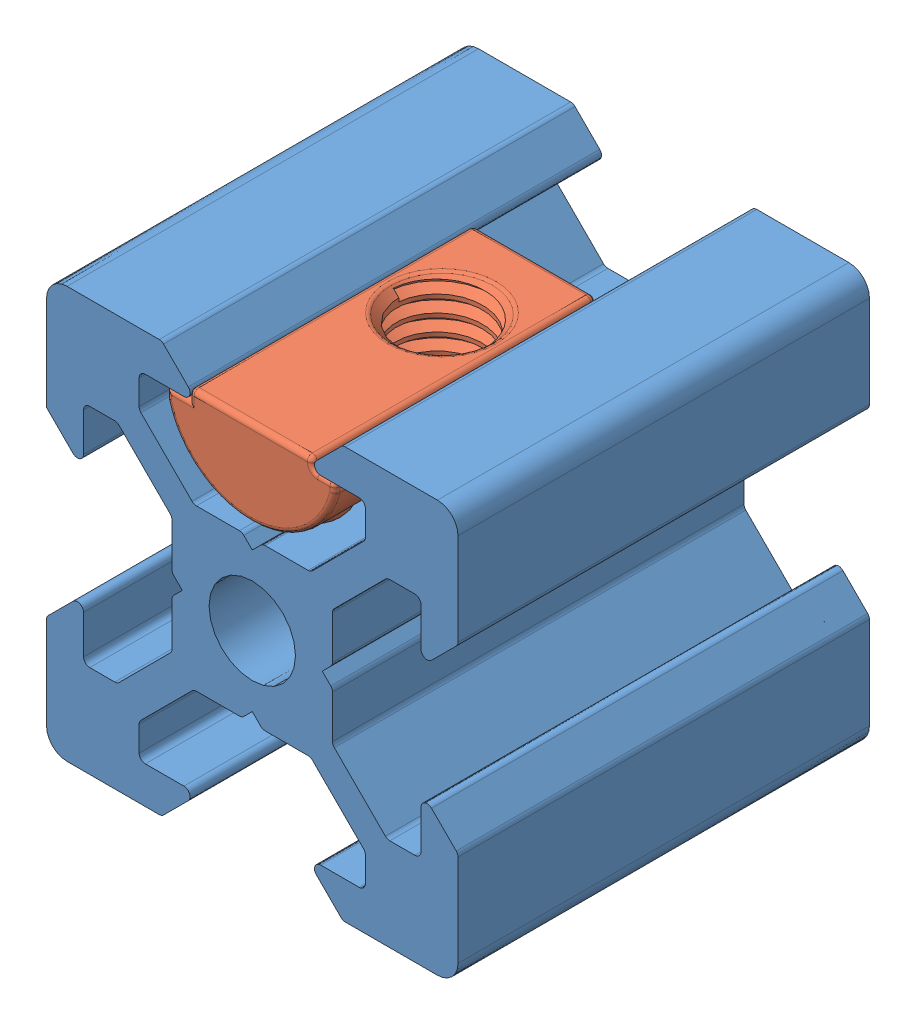
SolidWorks assembly Сборка Т-сухарь 6 паз с шариком, configuration По умолчанию. Lengths in mm.
Overall size (20 20 20).
2 component instances, 2 part files, 2 mates.
Components (placement in the parent):
- 2020V-1: 2020V [По умолчанию] at origin size (20 20 20)
- Т-Сухарь паз 6 с шариком-1: Т-Сухарь паз 6 с шариком [По умолчанию] at (-0.0786 4.5 13.1) x (-1 0 0) z (0 0 -1) size (8.2 5.46 13.8)
Mates (geometry in assembly coordinates):
- Совпадение1: coincident anti-aligned: plane of 2020V-1 through (-2.6 8.2 20) normal (0 -1 0); plane of Т-Сухарь паз 6-1 through (4.0214 8.2 20) normal (0 1 0)
- Совпадение3: coincident aligned: plane of 2020V-1 through (0 0 20) normal (0 0 1); plane of Т-Сухарь паз 6 с шариком-1 through (-0.0786 8.7266 20) normal (0 0 1)
